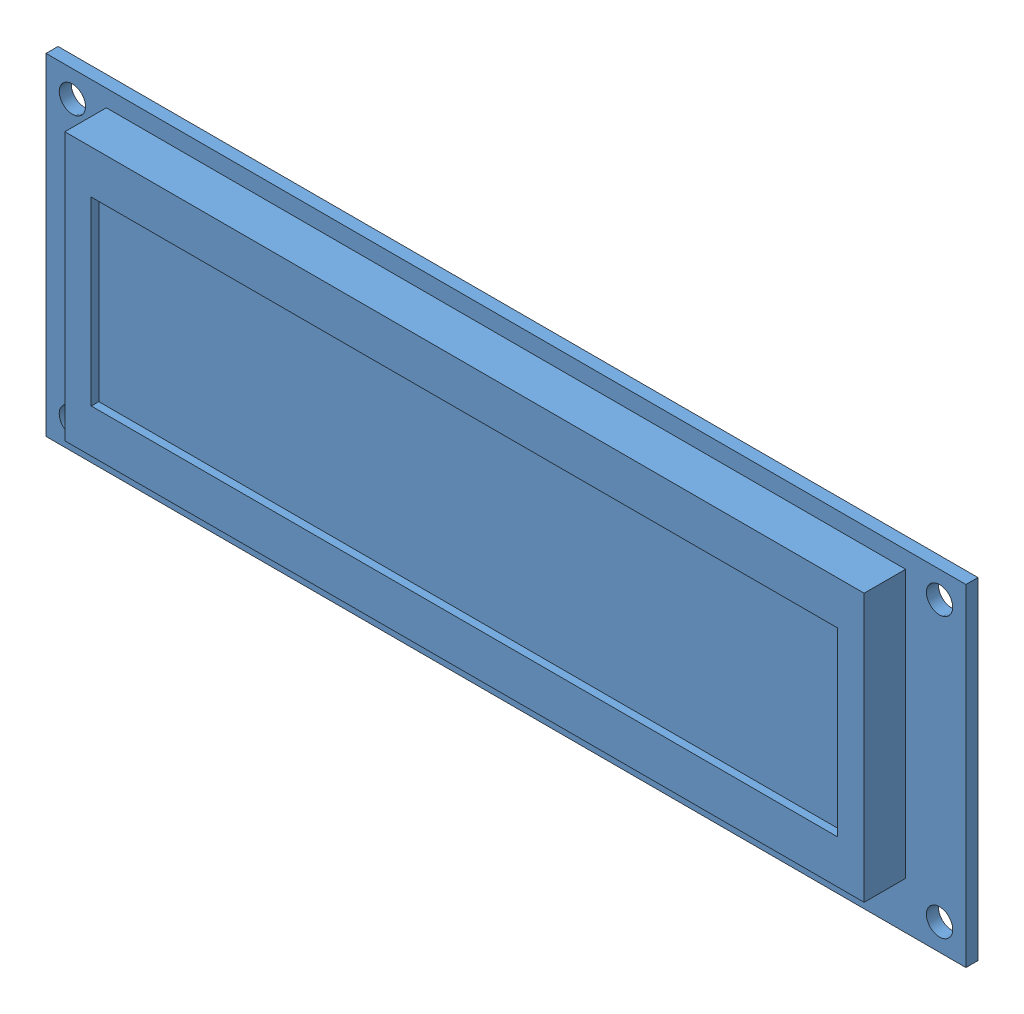
SolidWorks assembly lcd, configuration Default. Lengths in mm.
Overall size (122 44 15.99).
2 component instances, 2 part files, 0 mates.
Components (placement in the parent):
- JUMBO LCD-1: JUMBO LCD [Default] at origin size (122 44 7.1)
- zl201-16_p2-54_l40-6_w2-54_h8-9-1: zl201-16_p2-54_l40-6_w2-54_h8-9 [Default] at (10.98 2.5 0) x (1 0 0) z (0 1 0) size (40.64 11.94 2.54)
